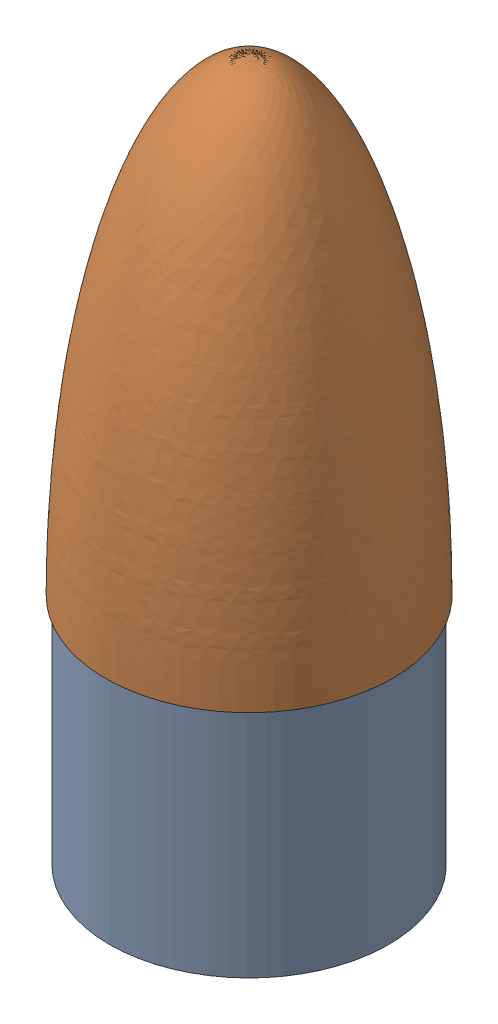
SolidWorks assembly FS_Fwd_Assembly, configuration Default. Lengths in mm.
Overall size (166.44 381 166.44).
2 component instances, 2 part files, 15 mates.
Components (placement in the parent):
- FS_Nosecone_Coupler-1: FS_Nosecone_Coupler [Default] at (457.7133 -219.8019 742.0151) x (0.995264 0 0.097211) z (-0.097211 0 0.995264) size (152.35 152.4 152.35)
- FS_Elliptical_Nosecone-1: FS_Elliptical_Nosecone [Default] at (457.7133 -92.8019 742.0151) size (156.72 254 156.72)
Mates (geometry in assembly coordinates):
- Concentric1: concentric anti-aligned: circle of 51 Tangent Ogive Nosecone-1; circle of 6in Coupler-1
- Distance1: distance = 88.9 mm anti-aligned: plane of FS_Nosecone_Coupler-1 through (457.7133 -67.4019 742.0151) normal (0 1 0); plane of 51 Tangent Ogive Nosecone-1 through (265.8159 146.0802 527.9394) normal (0 -1 0)
- Coincident2: coincident anti-aligned: plane of 51 Tangent Ogive Nosecone-1 through (265.8159 146.0802 527.9394) normal (0 -1 0); plane of FS_Fwd_Body_Tube-1 through (457.7133 -92.8019 742.0151) normal (0 1 0)
- Concentric4: concentric aligned: cylinder of FS_Nosecone_Coupler-1 through (457.7133 -67.4019 742.0151) axis (0 -1 0) radius 76.1746; cylinder of FS_Fwd_Body_Tube-1 through (457.7133 -92.8019 742.0151) axis (0 -1 0) radius 76.1746
- Concentric5: concentric aligned: cylinder of FS_Fwd_Body_Tube-1 through (457.7133 -92.8019 742.0151) axis (0 -1 0) radius 76.1746; cylinder of FS FWD Bulkhead-1 through (457.7133 -219.8019 742.0151) axis (0 -1 0) radius 73.025
- Concentric7: concentric anti-aligned: cylinder of FS FWD Bulkhead-1 through (457.7133 -219.8019 742.0151) axis (0 -1 0) radius 3.3; circle of 3014T45_Steel Eyebolt with Shoulder - for Lifting-1
- Coincident4: coincident anti-aligned: plane of FS FWD Bulkhead-1 through (457.7133 -229.3269 742.0151) normal (0 -1 0); plane of 3014T45_Steel Eyebolt with Shoulder - for Lifting-1 through (373.677 -315.8823 732.3432) normal (0 1 0)
- Concentric8: concentric anti-aligned: circle of FS FWD Bulkhead-1; circle of 92673A113_18-8 Stainless Steel Hex Nut-1
- Coincident5: coincident anti-aligned: plane of FS FWD Bulkhead-1 through (457.7133 -219.8019 742.0151) normal (0 1 0); plane of 92673A113_18-8 Stainless Steel Hex Nut-1 through (451.7703 -219.8019 744.4324) normal (0 -1 0)
- Concentric9: concentric aligned: cylinder of FS_Nosecone_Coupler-1 through (457.7133 -67.4019 742.0151) axis (0 -1 0) radius 76.1746; circle of FS_Nosecone(Elliptical)-1
- Distance2: distance = 25.4 mm anti-aligned: plane of FS_Elliptical_Nosecone-1 through (457.7133 -92.8019 742.0151) normal (0 -1 0); plane of FS_Nosecone_Coupler-1 through (457.7133 -67.4019 742.0151) normal (0 1 0)
- Coincident8: coincident anti-aligned: plane of FS_Fwd_Body_Tube-1 through (457.7133 -92.8019 742.0151) normal (0 1 0); plane of FS_Elliptical_Nosecone-1 through (457.7133 -92.8019 742.0151) normal (0 -1 0)
- Coincident9: coincident anti-aligned: plane of FS FWD Bulkhead-1 through (457.7133 -229.3269 742.0151) normal (0 -1 0); plane of 4843T11_Galvanized Steel Eyebolt - for Lifting-1 through (457.7133 -229.3269 742.0151) normal (0 1 0)
- Concentric10: concentric anti-aligned: cylinder of FS FWD Bulkhead-1 through (457.7133 -219.8019 742.0151) axis (0 -1 0) radius 3.3; circle of 4843T11_Galvanized Steel Eyebolt - for Lifting-1
- Coincident10: coincident aligned: circle of FS_Nosecone_Coupler-1; plane of FS FWD Bulkhead-1 through (457.7133 -219.8019 742.0151) normal (0 1 0)
